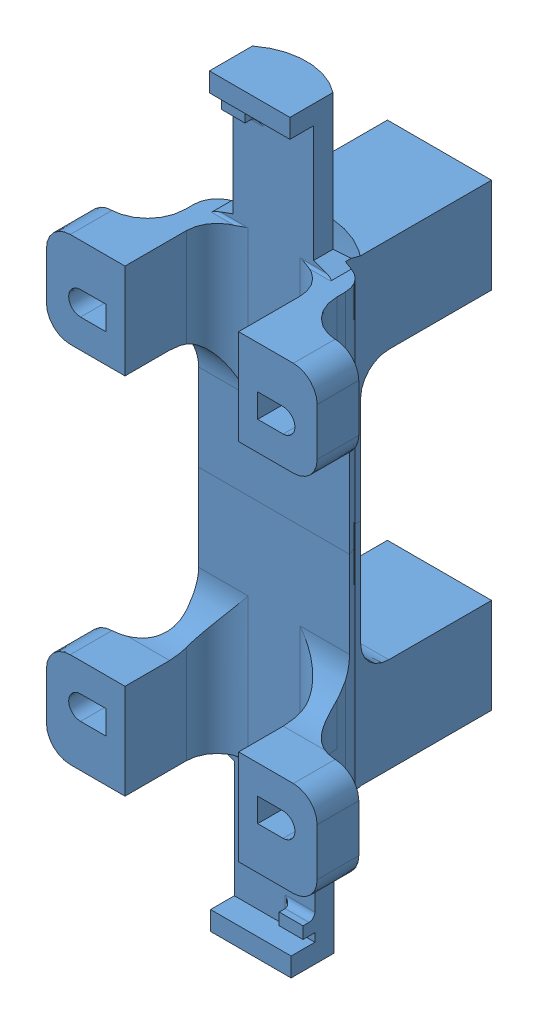
SolidWorks assembly DualMotorMount, configuration Default. Lengths in mm.
Overall size (28.89 79.48 27.5).
2 component instances, 1 part files, 2 mates.
Components (placement in the parent):
- DualMotorMount-3: DualMotorMount [Default] at (28.6255 7.946 -12.6634) size (28.89 39.74 27.5)
- DualMotorMount-4: DualMotorMount [Default] at (40.754 -20.734 -12.6634) x (-1 0 0) z (0 0 1) size (28.89 39.74 27.5)
Mates (geometry in assembly coordinates):
- Coincident2: coincident: circle of DualMotorMount-3; circle of DualMotorMount-4
- Coincident3: coincident anti-aligned: line of DualMotorMount-3 through (29.1335 -6.394 -14.2934) axis (1 0 0); line of DualMotorMount-4 through (40.246 -6.394 -14.2934) axis (-1 0 0)
